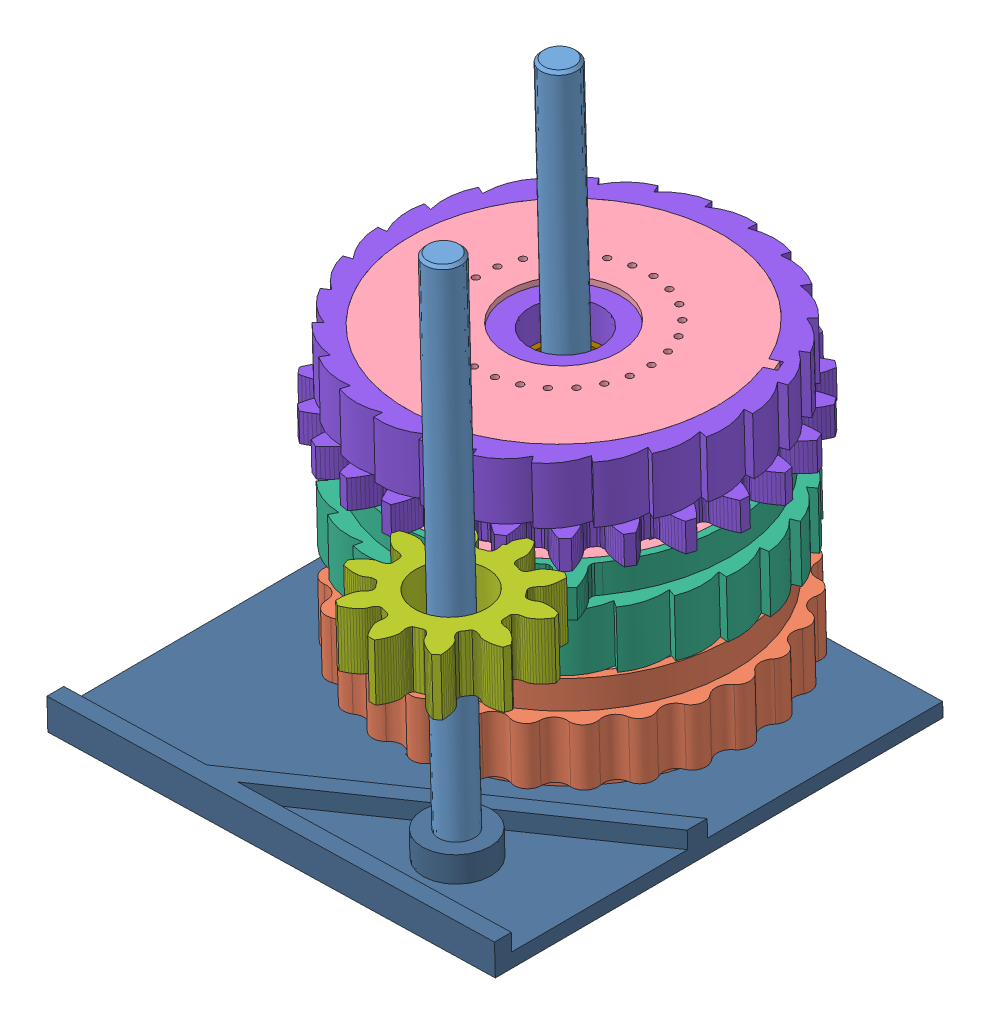
SolidWorks assembly Mockup assembly, configuration Default. Lengths in mm.
Overall size (106.9 102.1 115.25).
113 component instances, 17 part files, 22 mates.
Components (placement in the parent):
- Mounting bar-1: Mounting bar [Default] at (6.9063 -131.2975 9.0151) x (0.975576 0.024283 -0.218317) z (0.218335 0.001936 0.975872) size (6.35 101.6 6.35)
- Mounting bar-2: Mounting bar [Default] at (26.9712 -130.9526 49.7977) x (-0.610614 -0.012029 -0.791837) z (0.791561 0.021183 -0.610723) size (6.35 101.6 6.35)
- Battery 9V-1: Battery 9V [Default] at (-17.6533 -81.0908 69.2405) x (0.999709 0.024119 0.000115) z (0.000033 0.003415 -0.999994) size (25.91 48.13 16.26) (hidden)
- Letter selection wheel assembly-1: Letter selection wheel assembly [Default] at (-39.1633 -143.9496 -17.119) x (0.860229 0.022494 -0.509411) z (0.509336 0.009351 0.860517) size (72.37 17.5 74.83)
  - Letter selection wheel-1: Letter selection wheel [Default] at (26.602 23.0199 46.072) size (64.18 15 64.19)
  - ball bearing-1: ball bearing [6383K11] at (26.602 30.5199 46.072) x (1 0 0) z (0 -1 0) size (17.46 17.46 6.35)
  - PCB assembly-1: PCB assembly [Default] at (20.8498 33.5038 101.5951) x (1 0 0) z (0 1 0) size (67.78 70.24 3.5)
    - selector wheel PCB-2: selector wheel PCB [Default] at (5.7522 55.5231 3.5161) size (67.78 70.24 1)
    - spring pin-27: spring pin [Default] at (7.3927 81.0239 5.3161) x (1 0 0) z (0 -1 0) size (3.66 2.5 0.96)
    - spring pin-28: spring pin [Default] at (1.2423 80.6755 5.3161) x (0.970942 0.239316 0) z (0.239316 -0.970942 0) size (3.66 2.5 0.96)
    - spring pin-29: spring pin [Default] at (-4.6461 78.8653 5.3161) x (0.885456 0.464723 0) z (0.464723 -0.885456 0) size (3.66 2.5 0.96)
    - spring pin-30: spring pin [Default] at (-9.9301 75.6986 5.3161) x (0.748511 0.663123 0) z (0.663123 -0.748511 0) size (3.66 2.5 0.96)
    - spring pin-31: spring pin [Default] at (-14.3027 71.3593 5.3161) x (0.568065 0.822984 0) z (0.822984 -0.568065 0) size (3.66 2.5 0.96)
    - spring pin-32: spring pin [Default] at (-17.5098 66.0997 5.3161) x (0.354605 0.935016 0) z (0.935016 -0.354605 0) size (3.66 2.5 0.96)
    - spring pin-33: spring pin [Default] at (-19.365 60.2254 5.3161) x (0.120537 0.992709 0) z (0.992709 -0.120537 0) size (3.66 2.5 0.96)
    - spring pin-34: spring pin [Default] at (-19.7605 54.0778 5.3161) x (-0.120537 0.992709 0) z (0.992709 0.120537 0) size (3.66 2.5 0.96)
    - spring pin-35: spring pin [Default] at (-18.6732 48.0142 5.3161) x (-0.354605 0.935016 0) z (0.935016 0.354605 0) size (3.66 2.5 0.96)
    - spring pin-36: spring pin [Default] at (-16.1665 42.3871 5.3161) x (-0.568065 0.822984 0) z (0.822984 0.568065 0) size (3.66 2.5 0.96)
    - spring pin-37: spring pin [Default] at (-12.3859 37.5233 5.3161) x (-0.748511 0.663123 0) z (0.663123 0.748511 0) size (3.66 2.5 0.96)
    - spring pin-38: spring pin [Default] at (-7.5512 33.7056 5.3161) x (-0.885456 0.464723 0) z (0.464723 0.885456 0) size (3.66 2.5 0.96)
    - spring pin-39: spring pin [Default] at (-1.9434 31.1559 5.3161) x (-0.970942 0.239316 0) z (0.239316 0.970942 0) size (3.66 2.5 0.96)
    - spring pin-40: spring pin [Default] at (4.1117 30.0223 5.3161) x (-1 0 0) z (0 1 0) size (3.66 2.5 0.96)
    - spring pin-41: spring pin [Default] at (10.2621 30.3707 5.3161) x (-0.970942 -0.239316 0) z (-0.239316 0.970942 0) size (3.66 2.5 0.96)
    - spring pin-42: spring pin [Default] at (16.1505 32.1809 5.3161) x (-0.885456 -0.464723 0) z (-0.464723 0.885456 0) size (3.66 2.5 0.96)
    - spring pin-43: spring pin [Default] at (21.4345 35.3476 5.3161) x (-0.748511 -0.663123 0) z (-0.663123 0.748511 0) size (3.66 2.5 0.96)
    - spring pin-44: spring pin [Default] at (25.8071 39.6869 5.3161) x (-0.568065 -0.822984 0) z (-0.822984 0.568065 0) size (3.66 2.5 0.96)
    - spring pin-45: spring pin [Default] at (29.0142 44.9465 5.3161) x (-0.354605 -0.935016 0) z (-0.935016 0.354605 0) size (3.66 2.5 0.96)
    - spring pin-46: spring pin [Default] at (30.8694 50.8208 5.3161) x (-0.120537 -0.992709 0) z (-0.992709 0.120537 0) size (3.66 2.5 0.96)
    - spring pin-47: spring pin [Default] at (31.2649 56.9684 5.3161) x (0.120537 -0.992709 0) z (-0.992709 -0.120537 0) size (3.66 2.5 0.96)
    - spring pin-48: spring pin [Default] at (30.1776 63.032 5.3161) x (0.354605 -0.935016 0) z (-0.935016 -0.354605 0) size (3.66 2.5 0.96)
    - spring pin-49: spring pin [Default] at (27.6709 68.6591 5.3161) x (0.568065 -0.822984 0) z (-0.822984 -0.568065 0) size (3.66 2.5 0.96)
    - spring pin-50: spring pin [Default] at (23.8903 73.5229 5.3161) x (0.748511 -0.663123 0) z (-0.663123 -0.748511 0) size (3.66 2.5 0.96)
    - spring pin-51: spring pin [Default] at (19.0556 77.3406 5.3161) x (0.885456 -0.464723 0) z (-0.464723 -0.885456 0) size (3.66 2.5 0.96)
    - spring pin-52: spring pin [Default] at (13.4478 79.8903 5.3161) x (0.970942 -0.239316 0) z (-0.239316 -0.970942 0) size (3.66 2.5 0.96)
  - selector wheel PCB-3: selector wheel PCB [Default] at (26.602 23.0199 46.072) x (1 0 0) z (0 1 0) size (67.78 70.24 1)
- Scrambler wheel assembly-1: Scrambler wheel assembly [Default] at (15.8101 -126.3302 -45.8795) x (0.826758 0.018027 0.562268) z (-0.56204 -0.016384 0.826948) size (72.54 17.5 74.67)
  - Scrambler wheel-1: Scrambler wheel [Default] at (23.4146 24.3298 50.4806) size (65.8 15 63.85)
  - PCB assembly-1: PCB assembly [Default] at (17.9086 34.8137 106.1338) x (1 0 0) z (0 1 0) size (67.78 70.24 3.5)
    - selector wheel PCB-2: selector wheel PCB [Default] at (5.7522 55.5231 3.5161) size (67.78 70.24 1)
    - spring pin-27: spring pin [Default] at (7.3927 81.0239 5.3161) x (1 0 0) z (0 -1 0) size (3.66 2.5 0.96)
    - spring pin-28: spring pin [Default] at (1.2423 80.6755 5.3161) x (0.970942 0.239316 0) z (0.239316 -0.970942 0) size (3.66 2.5 0.96)
    - spring pin-29: spring pin [Default] at (-4.6461 78.8653 5.3161) x (0.885456 0.464723 0) z (0.464723 -0.885456 0) size (3.66 2.5 0.96)
    - spring pin-30: spring pin [Default] at (-9.9301 75.6986 5.3161) x (0.748511 0.663123 0) z (0.663123 -0.748511 0) size (3.66 2.5 0.96)
    - spring pin-31: spring pin [Default] at (-14.3027 71.3593 5.3161) x (0.568065 0.822984 0) z (0.822984 -0.568065 0) size (3.66 2.5 0.96)
    - spring pin-32: spring pin [Default] at (-17.5098 66.0997 5.3161) x (0.354605 0.935016 0) z (0.935016 -0.354605 0) size (3.66 2.5 0.96)
    - spring pin-33: spring pin [Default] at (-19.365 60.2254 5.3161) x (0.120537 0.992709 0) z (0.992709 -0.120537 0) size (3.66 2.5 0.96)
    - spring pin-34: spring pin [Default] at (-19.7605 54.0778 5.3161) x (-0.120537 0.992709 0) z (0.992709 0.120537 0) size (3.66 2.5 0.96)
    - spring pin-35: spring pin [Default] at (-18.6732 48.0142 5.3161) x (-0.354605 0.935016 0) z (0.935016 0.354605 0) size (3.66 2.5 0.96)
    - spring pin-36: spring pin [Default] at (-16.1665 42.3871 5.3161) x (-0.568065 0.822984 0) z (0.822984 0.568065 0) size (3.66 2.5 0.96)
    - spring pin-37: spring pin [Default] at (-12.3859 37.5233 5.3161) x (-0.748511 0.663123 0) z (0.663123 0.748511 0) size (3.66 2.5 0.96)
    - spring pin-38: spring pin [Default] at (-7.5512 33.7056 5.3161) x (-0.885456 0.464723 0) z (0.464723 0.885456 0) size (3.66 2.5 0.96)
    - spring pin-39: spring pin [Default] at (-1.9434 31.1559 5.3161) x (-0.970942 0.239316 0) z (0.239316 0.970942 0) size (3.66 2.5 0.96)
    - spring pin-40: spring pin [Default] at (4.1117 30.0223 5.3161) x (-1 0 0) z (0 1 0) size (3.66 2.5 0.96)
    - spring pin-41: spring pin [Default] at (10.2621 30.3707 5.3161) x (-0.970942 -0.239316 0) z (-0.239316 0.970942 0) size (3.66 2.5 0.96)
    - spring pin-42: spring pin [Default] at (16.1505 32.1809 5.3161) x (-0.885456 -0.464723 0) z (-0.464723 0.885456 0) size (3.66 2.5 0.96)
    - spring pin-43: spring pin [Default] at (21.4345 35.3476 5.3161) x (-0.748511 -0.663123 0) z (-0.663123 0.748511 0) size (3.66 2.5 0.96)
    - spring pin-44: spring pin [Default] at (25.8071 39.6869 5.3161) x (-0.568065 -0.822984 0) z (-0.822984 0.568065 0) size (3.66 2.5 0.96)
    - spring pin-45: spring pin [Default] at (29.0142 44.9465 5.3161) x (-0.354605 -0.935016 0) z (-0.935016 0.354605 0) size (3.66 2.5 0.96)
    - spring pin-46: spring pin [Default] at (30.8694 50.8208 5.3161) x (-0.120537 -0.992709 0) z (-0.992709 0.120537 0) size (3.66 2.5 0.96)
    - spring pin-47: spring pin [Default] at (31.2649 56.9684 5.3161) x (0.120537 -0.992709 0) z (-0.992709 -0.120537 0) size (3.66 2.5 0.96)
    - spring pin-48: spring pin [Default] at (30.1776 63.032 5.3161) x (0.354605 -0.935016 0) z (-0.935016 -0.354605 0) size (3.66 2.5 0.96)
    - spring pin-49: spring pin [Default] at (27.6709 68.6591 5.3161) x (0.568065 -0.822984 0) z (-0.822984 -0.568065 0) size (3.66 2.5 0.96)
    - spring pin-50: spring pin [Default] at (23.8903 73.5229 5.3161) x (0.748511 -0.663123 0) z (-0.663123 -0.748511 0) size (3.66 2.5 0.96)
    - spring pin-51: spring pin [Default] at (19.0556 77.3406 5.3161) x (0.885456 -0.464723 0) z (-0.464723 -0.885456 0) size (3.66 2.5 0.96)
    - spring pin-52: spring pin [Default] at (13.4478 79.8903 5.3161) x (0.970942 -0.239316 0) z (-0.239316 -0.970942 0) size (3.66 2.5 0.96)
  - ball bearing-1: ball bearing [6383K11] at (23.4146 31.8298 50.4806) x (1 0 0) z (0 -1 0) size (17.46 17.46 6.35)
  - selector wheel PCB-1: selector wheel PCB [Default] at (23.4146 24.3298 50.4806) x (1 0 0) z (0 1 0) size (67.78 70.24 1)
- small gear-1: small gear [Default] at (25.7645 -80.937 49.9685) x (-0.179073 -0.000961 -0.983835) z (0.02412 -0.999703 -0.003413) size (29.32 29.28 10)
- End cap wheel assembly-1: End cap wheel assembly [Default] at (43.7117 -111.6168 -36.1508) x (0.398797 0.006491 0.917016) z (-0.916722 -0.023479 0.398835) size (80.8 15 76.92)
  - endcap wheel-1: endcap wheel [Default] at (26.6122 32.7605 52.2161) size (68.11 15 68.39)
  - selector wheel PCB-1: selector wheel PCB [Default] at (26.8584 41.7605 52.3462) x (1 0 0) z (0 1 0) size (67.78 70.24 1)
  - selector wheel PCB-2: selector wheel PCB [Default] at (26.6122 28.7605 52.2161) x (-1 0 0) z (0 -1 0) size (67.78 70.24 1)
  - 57155K356 ball bearing-1: 57155K356 ball bearing [57155K356] at (26.6122 34.348 52.2161) x (-0.69888 0 -0.715239) z (0 -1 0) size (12.7 12.7 3.17)
- plunger wall assembly-1: plunger wall assembly [Default] at (-16.2635 -129.2285 -13.1206) x (-0.02412 0.999703 0.003413) z (0.999709 0.024119 0.000115) size (60 80 29) (hidden)
  - plunger wall-1: plunger wall [Default] at (33.8418 36.1419 63.1156) size (60 80 2.5)
  - plunger-1: plunger [Default] at (33.8418 15.9974 64.2656) x (1 0 0) z (0 1 0) size (20 25 28)
  - spring pin 4mm-1: spring pin 4mm [Default] at (34.3218 18.7839 56.3656) x (0 1 0) z (-1 0 0) size (4.05 4 0.96)
- indication panel assembly-1: indication panel assembly [Default] at (-28.8156 -63.5449 -15.7169) x (0.999709 0.024119 0.000115) z (0.02412 -0.999703 -0.003413) size (80 81.5 7)
  - LED panel-1: LED panel [Default] at (34.0802 38.962 59.6162) size (80 80 7)
  - indication pcb assembly-1: indication pcb assembly [Default] at (55.4357 -6.4979 102.4788) x (-1 0 0) z (0 0 -1) size (55 56.48 3.5)
    - indication PCB-1: indication PCB [Default] at (21.3555 31.4598 41.8626) size (55 56.48 1)
    - spring pin-1: spring pin [Default] at (43.9085 31.3248 43.6626) x (0.090499 -0.995897 0) z (-0.995897 -0.090499 0) size (3.66 2.5 0.96)
    - spring pin-27: spring pin [Default] at (43.2208 25.9314 43.6626) x (-0.150465 -0.988615 0) z (-0.988615 0.150465 0) size (3.66 2.5 0.96)
    - spring pin-28: spring pin [Default] at (41.2624 20.8593 43.6626) x (-0.382683 -0.92388 0) z (-0.92388 0.382683 0) size (3.66 2.5 0.96)
    - spring pin-29: spring pin [Default] at (38.1471 16.4033 43.6626) x (-0.592662 -0.805451 0) z (-0.805451 0.592662 0) size (3.66 2.5 0.96)
    - spring pin-30: spring pin [Default] at (34.0559 12.8224 43.6626) x (-0.768198 -0.640213 0) z (-0.640213 0.768198 0) size (3.66 2.5 0.96)
    - spring pin-31: spring pin [Default] at (29.2266 10.3245 43.6626) x (-0.899088 -0.437768 0) z (-0.437768 0.899088 0) size (3.66 2.5 0.96)
    - spring pin-32: spring pin [Default] at (23.9398 9.055 43.6626) x (-0.977727 -0.209881 0) z (-0.209881 0.977727 0) size (3.66 2.5 0.96)
    - spring pin-33: spring pin [Default] at (18.5029 9.0876 43.6626) x (-0.999544 0.030203 0) z (0.030203 0.999544 0) size (3.66 2.5 0.96)
    - spring pin-34: spring pin [Default] at (13.2318 10.4204 43.6626) x (-0.963271 0.268532 0) z (0.268532 0.963271 0) size (3.66 2.5 0.96)
    - spring pin-35: spring pin [Default] at (8.4328 12.9759 43.6626) x (-0.871016 0.491255 0) z (0.491255 0.871016 0) size (3.66 2.5 0.96)
    - spring pin-36: spring pin [Default] at (4.3848 16.6056 43.6626) x (-0.728141 0.685427 0) z (0.685427 0.728141 0) size (3.66 2.5 0.96)
    - spring pin-37: spring pin [Default] at (1.323 21.0986 43.6626) x (-0.542949 0.839766 0) z (0.839766 0.542949 0) size (3.66 2.5 0.96)
    - spring pin-38: spring pin [Default] at (-0.5745 26.1937 43.6626) x (-0.326203 0.9453 0) z (0.9453 0.326203 0) size (3.66 2.5 0.96)
    - spring pin-39: spring pin [Default] at (-1.1975 31.5949 43.6626) x (-0.090499 0.995897 0) z (0.995897 0.090499 0) size (3.66 2.5 0.96)
    - spring pin-40: spring pin [Default] at (-0.5098 36.9883 43.6626) x (0.150465 0.988615 0) z (0.988615 -0.150465 0) size (3.66 2.5 0.96)
    - spring pin-41: spring pin [Default] at (1.4486 42.0604 43.6626) x (0.382683 0.92388 0) z (0.92388 -0.382683 0) size (3.66 2.5 0.96)
    - spring pin-42: spring pin [Default] at (4.5639 46.5163 43.6626) x (0.592662 0.805451 0) z (0.805451 -0.592662 0) size (3.66 2.5 0.96)
    - spring pin-43: spring pin [Default] at (8.6551 50.0973 43.6626) x (0.768198 0.640213 0) z (0.640213 -0.768198 0) size (3.66 2.5 0.96)
    - spring pin-44: spring pin [Default] at (13.4844 52.5951 43.6626) x (0.899088 0.437768 0) z (0.437768 -0.899088 0) size (3.66 2.5 0.96)
    - spring pin-45: spring pin [Default] at (18.7711 53.8647 43.6626) x (0.977727 0.209881 0) z (0.209881 -0.977727 0) size (3.66 2.5 0.96)
    - spring pin-46: spring pin [Default] at (24.208 53.8321 43.6626) x (0.999544 -0.030203 0) z (-0.030203 -0.999544 0) size (3.66 2.5 0.96)
    - spring pin-47: spring pin [Default] at (29.4792 52.4993 43.6626) x (0.963271 -0.268532 0) z (-0.268532 -0.963271 0) size (3.66 2.5 0.96)
    - spring pin-48: spring pin [Default] at (34.2782 49.9438 43.6626) x (0.871016 -0.491255 0) z (-0.491255 -0.871016 0) size (3.66 2.5 0.96)
    - spring pin-49: spring pin [Default] at (38.3262 46.3141 43.6626) x (0.728141 -0.685427 0) z (-0.685427 -0.728141 0) size (3.66 2.5 0.96)
    - spring pin-50: spring pin [Default] at (41.3879 41.8211 43.6626) x (0.542949 -0.839766 0) z (-0.839766 -0.542949 0) size (3.66 2.5 0.96)
    - spring pin-51: spring pin [Default] at (43.2854 36.726 43.6626) x (0.326203 -0.9453 0) z (-0.9453 -0.326203 0) size (3.66 2.5 0.96)
    - spring pin-52: spring pin [Default] at (21.7527 46.348 43.6626) x (1 0 0) z (0 -1 0) size (3.66 2.5 0.96)
- ball bearing - small-1: ball bearing - small [57155K356] at (25.8851 -85.9355 49.9514) x (0.999709 0.024119 0.000105) z (0.02412 -0.999703 -0.003413) size (12.7 12.7 3.17) (hidden)
- ratchet wall assembly-1: ratchet wall assembly [Default] at (-94.0607 -54.9903 -11.1569) x (-0.000033 -0.003415 0.999994) z (0.999709 0.024119 0.000115) size (80 60 9.49) (hidden)
  - wall-1: wall [Default] at (34.4291 39.7574 59.0994) size (80 60 5.49)
  - spring pin 4mm-1: spring pin 4mm [Default] at (21.1291 22.7374 65.8394) x (1 0 0) z (0 -1 0) size (4.05 4 0.96)
  - spring pin 4mm-2: spring pin 4mm [Default] at (21.1291 45.2374 65.8394) x (1 0 0) z (0 -1 0) size (4.05 4 0.96)
Mates (geometry in assembly coordinates):
- Coincident3: coincident aligned: plane of Mounting bar-1 through (4.4557 -29.7276 9.3618) normal (-0.02412 0.999703 0.003413); plane of Mounting bar-2 through (24.5206 -29.3828 50.1445) normal (-0.02412 0.999703 0.003413)
- Concentric7: concentric aligned: cylinder of Mounting bar-1 through (4.4557 -29.7276 9.3618) axis (0.02412 -0.999703 -0.003413) radius 3.175; cylinder of Letter selection wheel assembly-1/ball bearing-1 through (6.5271 -115.5837 9.0687) axis (0.02412 -0.999703 -0.003413) radius 2.3813
- Concentric8: concentric aligned: cylinder of Mounting bar-1 through (4.4557 -29.7276 9.3618) axis (0.02412 -0.999703 -0.003413) radius 3.175; cylinder of Scrambler wheel assembly-1/ball bearing-1 through (6.105 -98.0889 9.1284) axis (0.02412 -0.999703 -0.003413) radius 2.3813
- Concentric10: concentric anti-aligned: cylinder of Mounting bar-2 through (24.5206 -29.3828 50.1445) axis (0.02412 -0.999703 -0.003413) radius 3.175; cylinder of small gear-1 through (26.0057 -90.934 49.9343) axis (-0.02412 0.999703 0.003413) radius 6.35
- Coincident9: coincident: line of Letter selection wheel assembly-1/PCB assembly-1/spring pin-49 through (17.8926 -102.0532 -13.5777) axis (-0.418619 -0.0132 0.908066); plane of Scrambler wheel assembly-1/selector wheel PCB-1 through (6.2094 -102.4126 9.1137) normal (0.02412 -0.999703 -0.003413)
- Concentric11: concentric aligned: cylinder of Mounting bar-1 through (4.4557 -29.7276 9.3618) axis (0.02412 -0.999703 -0.003413) radius 3.175; cylinder of ? through (5.683 -80.594 9.1882) axis (0.02412 -0.999703 -0.003413) radius 2.3813
- Coincident12: coincident: line of Scrambler wheel assembly-1/PCB assembly-1/spring pin-50 through (29.9942 -84.318 4.5525) axis (0.968935 0.024218 -0.246127); plane of End cap wheel assembly-1/selector wheel PCB-2 through (5.7873 -84.9178 9.1734) normal (0.02412 -0.999703 -0.003413)
- Coincident29: coincident anti-aligned: plane of plunger wall assembly-1/plunger wall-1 through (46.0164 -93.9978 23.1438) normal (-0.999709 -0.024119 -0.000115); plane of indication panel assembly-1/LED panel-1 through (46.7386 -124.1255 63.0412) normal (0.999709 0.024119 0.000115)
- Coincident31: coincident aligned: plane of plunger wall assembly-1/plunger wall-1 through (49.2379 -124.0652 63.0415) normal (-0.000033 -0.003415 0.999994); plane of indication panel assembly-1/LED panel-1 through (-33.2381 -126.0551 63.0319) normal (-0.000033 -0.003415 0.999994)
- Coincident32: coincident: plane of Letter selection wheel assembly-1/selector wheel PCB-3 through (6.6315 -119.9074 9.0539) normal (0.02412 -0.999703 -0.003413); moEndPointRef_w of indication panel assembly-1/indication pcb assembly-1/spring pin-46
- Concentric12: concentric aligned: cylinder of Mounting bar-1 through (4.4557 -29.7276 9.3618) axis (0.02412 -0.999703 -0.003413) radius 3.175; circle of indication panel assembly-1/LED panel-1
- Concentric13: concentric anti-aligned: cylinder of small gear-1 through (26.0057 -90.934 49.9343) axis (-0.02412 0.999703 0.003413) radius 6.35; cylinder of ball bearing - small-1 through (25.9234 -87.5225 49.946) axis (0.02412 -0.999703 -0.003413) radius 6.35
- Width1: width aligned: plane of small gear-1 through (25.7645 -80.937 49.9685) normal (-0.02412 0.999703 0.003413); plane of small gear-1 through (26.0057 -90.934 49.9343) normal (0.02412 -0.999703 -0.003413); plane of ball bearing - small-1 through (25.8466 -84.3696 56.148) normal (-0.02412 0.999703 0.003413); plane of ball bearing - small-1 through (25.9232 -87.5437 56.1372) normal (0.02412 -0.999703 -0.003413)
- Coincident30: coincident aligned: plane of plunger wall assembly-1/plunger wall-1 through (49.2379 -124.0652 63.0415) normal (0.02412 -0.999703 -0.003413); plane of indication panel assembly-1/LED panel-1 through (6.7516 -124.9537 23.0368) normal (0.02412 -0.999703 -0.003413)
- Coincident47: coincident aligned: line of indication panel assembly-1/LED panel-1 through (-33.2983 -123.5456 60.0405) axis (0.000033 0.003415 -0.999994); line of ratchet wall assembly-1/wall-1 through (-33.2984 -123.5558 63.0405) axis (0.000033 0.003415 -0.999994)
- Coincident49: coincident aligned: plane of indication panel assembly-1/LED panel-1 through (-33.2354 -125.7819 -16.9676) normal (0.000033 0.003415 -0.999994); plane of ratchet wall assembly-1/wall-1 through (-30.7965 -123.2223 -16.9588) normal (0.000033 0.003415 -0.999994)
- Parallel3: parallel aligned: plane of indication panel assembly-1/LED panel-1 through (6.6913 -122.4544 23.0453) normal (-0.02412 0.999703 0.003413); plane of ratchet wall assembly-1/wall-1 through (-32.2437 -63.2401 -16.754) normal (-0.02412 0.999703 0.003413)
- Distance1: distance = 5 mm anti-aligned: plane of Battery 9V-1 through (-26.9202 -118.3847 58.4116) normal (0.02412 -0.999703 -0.003413); plane of indication panel assembly-1/LED panel-1 through (6.6913 -122.4544 23.0453) normal (-0.02412 0.999703 0.003413)
- Coincident57: coincident anti-aligned: plane of Battery 9V-1 through (-30.9044 -119.1329 63.3619) normal (-0.999709 -0.024119 -0.000115); plane of ratchet wall assembly-1/wall-1 through (-31.5214 -93.3678 23.1434) normal (0.999709 0.024119 0.000115)
- Distance2: distance = 1.363 mm aligned: plane of small gear-1 through (25.7645 -80.937 49.9685) normal (-0.02412 0.999703 0.003413); plane of End cap wheel assembly-1/endcap wheel-1 through (5.6667 -79.9192 9.1905) normal (-0.02412 0.999703 0.003413)
- Distance3: distance = 0.8 mm: line of small gear-1 through (16.2925 -81.1269 38.6622) axis (0.791218 0.021176 -0.611167); plane of End cap wheel assembly-1/endcap wheel-1 through (23.1648 -84.5778 32.3983) normal (0.611058 0.012041 0.791494)
- Distance4: distance = 6.3935 mm aligned: plane of indication panel assembly-1/LED panel-1 through (6.7516 -124.9537 23.0368) normal (0.02412 -0.999703 -0.003413); plane of Mounting bar-2 through (26.9712 -130.9526 49.7977) normal (0.02412 -0.999703 -0.003413)
